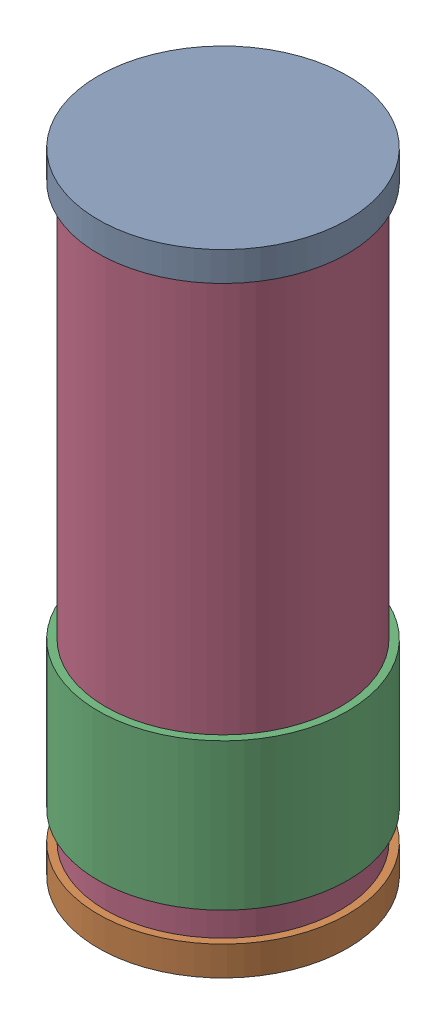
SolidWorks assembly D3, configuration Default. Lengths in mm.
Overall size (1.7 4.3 1.7).
8 component instances, 4 part files, 0 mates.
Components (placement in the parent):
- 756963648-1: 756963648 [Default] at (21.3502 43.0001 -1.7115) x (-1 0 0) z (0 1 0) size (1.7 1.7 0.2)
  - Cylinder (3)-1: Cylinder (3) [Default] at origin size (1.7 1.7 0.2)
- 756963528-1: 756963528 [Default] at (21.3501 39.0999 -1.7115) x (-1 0 0) z (0 -1 0) size (1.7 1.7 0.2)
  - Cylinder (4)-1: Cylinder (4) [Default] at origin size (1.7 1.7 0.2)
- 756963408-1: 756963408 [Default] at (21.3501 40.2999 -1.7115) x (-1 0 0) z (0 -1 0) size (1.7 1.7 1)
  - Cylinder (5)-1: Cylinder (5) [Default] at origin size (1.7 1.7 1)
- 756962328-1: 756962328 [Default] at (21.3501 43.0499 -1.7115) x (-1 0 0) z (0 -1 0) size (1.6 1.6 4)
  - Cylinder (6)-1: Cylinder (6) [Default] at origin size (1.6 1.6 4)
